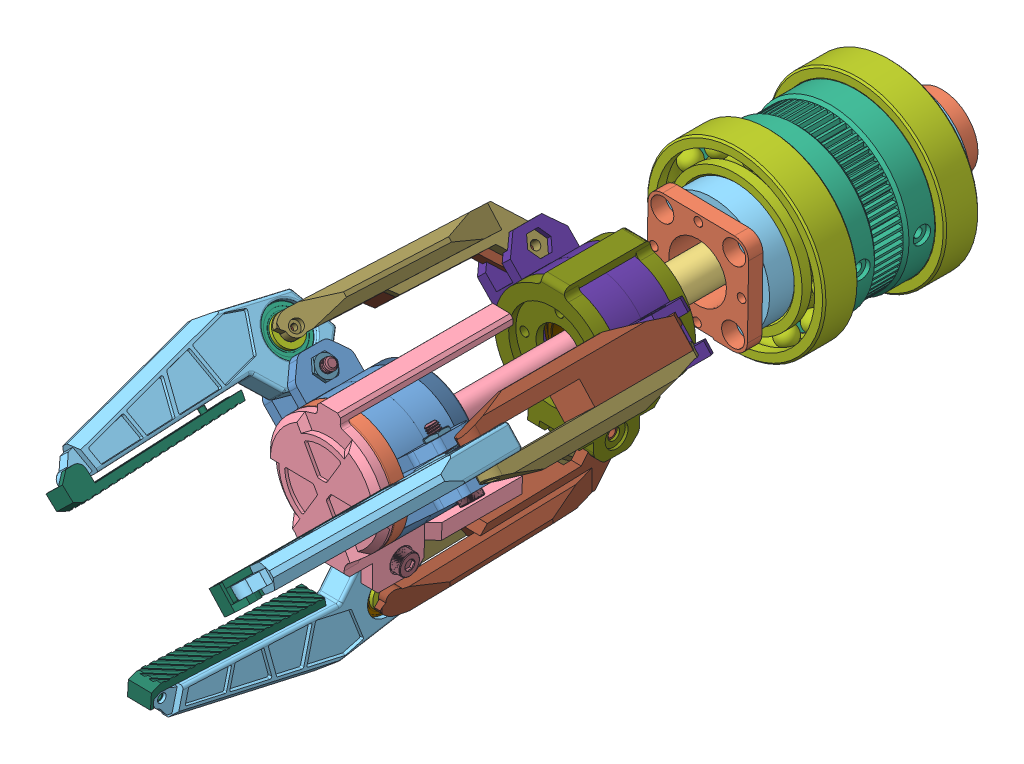
SolidWorks assembly CrawAssemV1.2, configuration EX2. Lengths in mm.
Overall size (95.83 96.83 278.95).
52 component instances, 26 part files, 110 mates.
Components (placement in the parent):
- CrawPivotL-1: CrawPivotL [Default] at (23.6534 28.2906 36.4169) x (0.675201 -0.737634 0) z (0 0 1)
- RotorInner-1: RotorInner [Default] at (23.6534 28.2906 51.4169) x (-0.675201 0.737634 0) z (0 0 -1)
- 4668K131_Permanently Lubricated Stainless Steel Ball Bearing-1: 4668K131_Permanently Lubricated Stainless Steel Ball Bearing [4668K131] at (23.6534 28.2906 52.4169) x (0.977927 0.208948 0) z (0 0 1)
- RotorOutter-1: RotorOutter [Default] at (23.6534 28.2906 56.4169) x (-0.999871 0.016078 0) z (0 0 -1)
- CrawPivotL-2: CrawPivotL [Default] at (23.6534 28.2906 36.4169) x (-0.716673 -0.697409 0) z (0 0 -1)
- FrontCraw-1: FrontCraw [Default] at (-7.9204 40.6623 113.525) x (-0.024761 0.025445 -0.99937) z (0.69697 -0.716221 -0.035504)
- FrontCraw-2: FrontCraw [Default] at (49.7643 43.7862 113.4714) x (0.035168 0.032192 -0.998863) z (-0.736795 -0.674433 -0.047677)
- 4668K334_Permanently Lubricated Stainless Steel Ball Bearing-1: 4668K334_Permanently Lubricated Stainless Steel Ball Bearing [4668K334] at (58.2277 46.2461 36.989) x (0.461728 0.422648 0.779857) z (-0.675201 0.737634 0)
- BearingStop1-1: BearingStop1 [Default] at (56.5397 48.0902 36.989) x (-0.727461 -0.665889 0.165503) z (0.675201 -0.737634 0)
- 4668K334_Permanently Lubricated Stainless Steel Ball Bearing-2: 4668K334_Permanently Lubricated Stainless Steel Ball Bearing [4668K334] at (-9.9873 48.3784 36.952) x (0.471273 -0.484291 0.737132) z (-0.716673 -0.697409 0)
- BearingStop1-2: BearingStop1 [Default] at (-11.779 46.6349 36.952) x (-0.683695 0.702579 -0.197341) z (0.716673 0.697409 0)
- BearingStop2-1: BearingStop2 [Default] at (55.6957 49.0123 36.989) x (-0.727461 -0.665889 0.165503) z (0.675201 -0.737634 0)
- BearingStop2-2: BearingStop2 [Default] at (-12.6749 45.7632 36.952) x (-0.683695 0.702579 -0.197341) z (0.716673 0.697409 0)
- FrontCraw-3: FrontCraw [Default] at (27.1452 -3.3521 113.4714) x (-0.000767 -0.047671 -0.998863) z (0.016059 0.998734 -0.047677)
- 7804K117_Stainless Steel Ball Bearing-1: 7804K117_Stainless Steel Ball Bearing [7804K117] at (23.1186 -11.1922 36.989) x (-0.007051 -0.438494 -0.898707) z (0.999871 -0.016078 0)
- BearingStop2-3: BearingStop2 [Default] at (19.3691 -11.1319 36.989) x (0.016038 0.997394 0.070343) z (0.999871 -0.016078 0)
- BearingStop1-3: BearingStop1 [Default] at (20.6189 -11.152 36.989) x (0.016038 0.997394 0.070343) z (0.999871 -0.016078 0)
- RotorInnerBack-1: RotorInnerBack [Default] at (23.6534 28.2906 21.4169) x (0.962311 -0.271952 0) z (0 0 1)
- SEC2pull1-1: SEC2pull1 [Default] at (-10.6231 40.787 37.118) x (0.023165 -0.023805 -0.999448) z (0.716673 0.697409 0)
- SEC2pull2-1: SEC2pull2 [Default] at (-3.4564 47.7611 37.118) x (0.023165 -0.023805 -0.999448) z (0.716673 0.697409 0)
- 91290A164_Black-Oxide Alloy Steel Socket Head Screw-1: 91290A164_Black-Oxide Alloy Steel Socket Head Screw [91290A164] at (23.2113 0.7942 36.4169) x (0.000258 0.016076 -0.999871) z (0.999871 -0.016078 0)
- 90592A090_Steel Hex Nut (1)-1: 90592A090_Steel Hex Nut (1) [90592A090] at (14.6124 0.9324 36.4169) x (0.016078 0.999871 0) z (0 0 1)
- 91290A164_Black-Oxide Alloy Steel Socket Head Screw-2: 91290A164_Black-Oxide Alloy Steel Socket Head Screw [91290A164] at (-0.6785 40.3897 36.4169) x (-0.0003 0.000308 -1) z (-0.716673 -0.697409 0)
- 90592A090_Steel Hex Nut (1)-2: 90592A090_Steel Hex Nut (1) [90592A090] at (4.0516 44.9926 36.4169) x (-0.348705 0.358336 -0.866025) z (-0.603974 0.620657 0.5)
- 91290A164_Black-Oxide Alloy Steel Socket Head Screw-3: 91290A164_Black-Oxide Alloy Steel Socket Head Screw [91290A164] at (48.6435 38.9643 36.4169) x (-0.209995 -0.192222 0.95862) z (0.675201 -0.737634 0)
- 90592A090_Steel Hex Nut (1)-3: 90592A090_Steel Hex Nut (1) [90592A090] at (44.1872 43.8327 36.4169) x (-0.368817 -0.3376 -0.866025) z (-0.63881 -0.584741 0.5)
- UpperSecCraw (1)-1: UpperSecCraw (1) [Default] at (-7.216 44.2401 113.6369) x (-0.024761 0.025445 -0.99937) z (0.716673 0.697409 0)
- UpperSecCraw (1)-2: UpperSecCraw (1) [Default] at (24.1122 -5.3749 113.6086) x (-0.000767 -0.047671 -0.998863) z (-0.999871 0.016078 0)
- UpperSecCraw (1)-3: UpperSecCraw (1) [Default] at (53.3178 42.9719 113.6086) x (0.035168 0.032192 -0.998863) z (0.675201 -0.737634 0)
- RTL-1: RTL [Default] at (23.6534 28.2906 -18.4955) x (-0.999871 0.016078 0) z (0 0 -1)
- PullPivot-1: PullPivot [Default] at (23.6534 28.2906 -38.4955) x (0.675201 -0.737634 0) z (0 0 1)
- 5972K213_Ball Bearing-1: 5972K213_Ball Bearing [5972K213] at (23.6534 28.2906 -33.4955)
- PullPivot2-1: PullPivot2 [Default] at (23.6534 28.2906 -38.4955) x (0.999025 -0.044147 0) z (0 0 1)
- PullPivot-2: PullPivot [Default] at (23.6534 28.2906 -38.4955) x (-0.716673 -0.697409 0) z (0 0 -1)
- 5972K213_Ball Bearing-2: 5972K213_Ball Bearing [5972K213] at (23.6534 28.2906 -43.4955) x (0.923728 0.383049 0) z (0 0 -1)
- PullPivot2-2: PullPivot2 [Default] at (23.6534 28.2906 -38.4955) x (-0.716673 -0.697409 0) z (0 0 -1)
- SEC2pull1-4: SEC2pull1 [Default] at (50.6589 47.1131 37.1398) x (-0.022244 -0.020361 -0.999545) z (0.675201 -0.737634 0)
- SEC2pull1-5: SEC2pull1 [Default] at (29.1982 -6.2916 37.1398) x (0.000485 0.030152 -0.999545) z (-0.999871 0.016078 0)
- SEC2pull2-7: SEC2pull2 [Default] at (19.5494 -6.1365 37.1398) x (0.000485 0.030152 -0.999545) z (-0.999871 0.016078 0)
- SEC2pull2-8: SEC2pull2 [Default] at (57.4109 39.7367 37.1398) x (-0.022244 -0.020361 -0.999545) z (0.675201 -0.737634 0)
- CylinderTube-1: CylinderTube [Default] at (23.6534 28.2906 -74.2503) x (-0.999871 0.016078 0) z (-0.016078 -0.999871 0)
- Hydro2-2: Hydro2 [Default] at (23.6534 28.2906 -50.4955) x (-0.999871 0.016078 0) z (0 0 -1) size (30 30 73)
- 6112K44_Linear Motion Shaft-1: 6112K44_Linear Motion Shaft [6112K44] at (23.6534 28.2906 -52.5831) x (-0.201275 -0.979535 0) z (0 0 1) size (8 8 100)
- Cylinder40mmCover-1: Cylinder40mmCover [Default] at (23.6534 28.2906 -79.2503) x (-0.999871 0.016078 0) z (0 0 -1) size (40 40 70)
- PiV1-1: PiV1 [Default] at (23.6534 28.2906 -129.2503) x (0.999871 -0.016078 0) z (0 0 1) size (55 55 30)
- PiVEnclosure1-1: PiVEnclosure1 [Default] at (23.6534 28.2906 -109.2503) x (0.791208 -0.611547 0) z (0 0 1) size (75 75 13) (hidden)
- 4668K334_Permanently Lubricated Stainless Steel Ball Bearing-3: 4668K334_Permanently Lubricated Stainless Steel Ball Bearing [4668K334] at (19.2674 62.5359 -106.7503) (hidden)
- 4668K334_Permanently Lubricated Stainless Steel Ball Bearing-4: 4668K334_Permanently Lubricated Stainless Steel Ball Bearing [4668K334] at (-10.5918 23.9046 -106.7503) (hidden)
- 4668K334_Permanently Lubricated Stainless Steel Ball Bearing-5: 4668K334_Permanently Lubricated Stainless Steel Ball Bearing [4668K334] at (28.0395 -5.9546 -106.7503) (hidden)
- 4668K334_Permanently Lubricated Stainless Steel Ball Bearing-6: 4668K334_Permanently Lubricated Stainless Steel Ball Bearing [4668K334] at (57.8987 32.6767 -106.7503) (hidden)
- 5972K249_Ball Bearing-1: 5972K249_Ball Bearing [5972K249] at (23.6534 28.2906 -93.2503) x (0.88466 0.466238 0) z (0 0 1) size (62 62 12)
- 5972K249_Ball Bearing-2: 5972K249_Ball Bearing [5972K249] at (23.6534 28.2906 -135.2503) x (0.910111 -0.414364 0) z (0 0 1) size (62 62 12)
Mates (geometry in assembly coordinates):
- Concentric1: concentric aligned: cylinder of CrawPivotL-1 through (36.9309 40.4442 36.4169) axis (0 0 1) radius 1.3; cylinder of RotorInner-1 through (36.9309 40.4442 43.4169) axis (0 0 1) radius 1.15
- Concentric2: concentric aligned: circle of CrawPivotL-1; cylinder of RotorInner-1 through (40.8175 22.8689 43.4169) axis (0 0 1) radius 1.15
- Coincident2: coincident anti-aligned: plane of CrawPivotL-1 through (23.6534 28.2906 46.4169) normal (0 0 1); plane of RotorInner-1 through (23.6534 28.2906 46.4169) normal (0 0 -1)
- Concentric3: concentric anti-aligned: cylinder of RotorInner-1 through (23.6534 28.2906 54.9169) axis (0 0 -1) radius 3.85; cylinder of 4668K131_Permanently Lubricated Stainless Steel Ball Bearing-1 through (23.6534 28.2906 54.4169) axis (0 0 1) radius 4
- Coincident3: coincident anti-aligned: plane of RotorInner-1 through (23.6534 28.2906 50.4169) normal (0 0 1); plane of 4668K131_Permanently Lubricated Stainless Steel Ball Bearing-1 through (22.4926 33.7235 50.4169) normal (0 0 -1)
- Concentric4: concentric anti-aligned: cylinder of 4668K131_Permanently Lubricated Stainless Steel Ball Bearing-1 through (23.6534 28.2906 54.4169) axis (0 0 1) radius 8; cylinder of RotorOutter-1 through (23.6534 28.2906 54.4169) axis (0 0 -1) radius 8
- Coincident4: coincident anti-aligned: plane of 4668K131_Permanently Lubricated Stainless Steel Ball Bearing-1 through (22.0237 35.9184 54.4169) normal (0 0 1); plane of RotorOutter-1 through (23.6534 28.2906 54.4169) normal (0 0 -1)
- Coincident5: coincident anti-aligned: plane of CrawPivotL-1 through (23.6534 28.2906 36.4169) normal (0 0 -1); plane of CrawPivotL-2 through (23.6534 28.2906 36.4169) normal (0 0 1)
- Coincident6: coincident anti-aligned: circle of CrawPivotL-1; circle of CrawPivotL-2
- Concentric7: concentric anti-aligned: cylinder of FrontCraw-2 through (56.5397 48.0902 36.989) axis (0.675201 -0.737634 0) radius 8; cylinder of 4668K334_Permanently Lubricated Stainless Steel Ball Bearing-1 through (56.5397 48.0902 36.989) axis (-0.675201 0.737634 0) radius 8
- Coincident10: coincident anti-aligned: plane of FrontCraw-2 through (56.5397 48.0902 36.989) normal (0.675201 -0.737634 0); plane of 4668K334_Permanently Lubricated Stainless Steel Ball Bearing-1 through (60.9979 52.1711 32.1378) normal (-0.675201 0.737634 0)
- Concentric8: concentric aligned: cylinder of 4668K334_Permanently Lubricated Stainless Steel Ball Bearing-1 through (56.5397 48.0902 36.989) axis (-0.675201 0.737634 0) radius 4; cylinder of BearingStop1-1 through (59.9157 44.4021 36.989) axis (-0.675201 0.737634 0) radius 3.9
- Coincident11: coincident anti-aligned: plane of 4668K334_Permanently Lubricated Stainless Steel Ball Bearing-1 through (63.0477 47.2689 33.581) normal (0.675201 -0.737634 0); plane of BearingStop1-1 through (59.9157 44.4021 36.989) normal (-0.675201 0.737634 0)
- Concentric9: concentric anti-aligned: cylinder of FrontCraw-1 through (-11.779 46.6349 36.952) axis (0.716673 0.697409 0) radius 8; cylinder of 4668K334_Permanently Lubricated Stainless Steel Ball Bearing-2 through (-11.779 46.6349 36.952) axis (-0.716673 -0.697409 0) radius 8
- Coincident12: coincident anti-aligned: plane of FrontCraw-1 through (-11.779 46.6349 36.952) normal (0.716673 0.697409 0); plane of 4668K334_Permanently Lubricated Stainless Steel Ball Bearing-2 through (-15.7632 50.7291 42.189) normal (-0.716673 -0.697409 0)
- Concentric11: concentric aligned: cylinder of 4668K334_Permanently Lubricated Stainless Steel Ball Bearing-2 through (-11.779 46.6349 36.952) axis (-0.716673 -0.697409 0) radius 4; cylinder of BearingStop1-2 through (-8.1957 50.122 36.952) axis (-0.716673 -0.697409 0) radius 3.9
- Coincident13: coincident anti-aligned: plane of 4668K334_Permanently Lubricated Stainless Steel Ball Bearing-2 through (-10.9946 52.9982 40.631) normal (0.716673 0.697409 0); plane of BearingStop1-2 through (-8.1957 50.122 36.952) normal (-0.716673 -0.697409 0)
- Concentric12: concentric aligned: cylinder of BearingStop1-1 through (60.7598 43.48 36.989) axis (-0.675201 0.737634 0) radius 3.05; cylinder of BearingStop2-1 through (60.591 43.6644 36.989) axis (-0.675201 0.737634 0) radius 2.95
- Coincident15: coincident anti-aligned: circle of BearingStop1-1; plane of BearingStop2-1 through (56.5397 48.0902 36.989) normal (0.675201 -0.737634 0)
- Concentric13: concentric aligned: cylinder of BearingStop1-2 through (-7.2998 50.9937 36.952) axis (-0.716673 -0.697409 0) radius 3.05; cylinder of BearingStop2-2 through (-7.479 50.8194 36.952) axis (-0.716673 -0.697409 0) radius 2.95
- Coincident17: coincident anti-aligned: plane of BearingStop1-2 through (-11.779 46.6349 36.952) normal (-0.716673 -0.697409 0); plane of BearingStop2-2 through (-11.779 46.6349 36.952) normal (0.716673 0.697409 0)
- Concentric14: concentric aligned: circle of RotorOutter-1; circle of FrontCraw-3
- Coincident18: coincident anti-aligned: plane of RotorOutter-1 through (27.1465 -3.2696 56.4169) normal (-0.999871 0.016078 0); plane of FrontCraw-3 through (27.1452 -3.3521 113.4714) normal (0.999871 -0.016078 0)
- Concentric15: concentric anti-aligned: cylinder of FrontCraw-3 through (25.6183 -11.2324 36.989) axis (-0.999871 0.016078 0) radius 8; cylinder of 7804K117_Stainless Steel Ball Bearing-1 through (25.6183 -11.2324 36.989) axis (0.999871 -0.016078 0) radius 8
- Coincident20: coincident anti-aligned: plane of FrontCraw-3 through (25.6183 -11.2324 36.989) normal (-0.999871 0.016078 0); plane of 7804K117_Stainless Steel Ball Bearing-1 through (25.698 -6.2754 34.5697) normal (0.999871 -0.016078 0)
- Concentric16: concentric anti-aligned: cylinder of 7804K117_Stainless Steel Ball Bearing-1 through (25.6183 -11.2324 36.989) axis (0.999871 -0.016078 0) radius 4; cylinder of BearingStop1-3 through (25.6183 -11.2324 36.989) axis (-0.999871 0.016078 0) radius 3.9
- Coincident21: coincident anti-aligned: plane of 7804K117_Stainless Steel Ball Bearing-1 through (25.698 -6.2754 34.5697) normal (0.999871 -0.016078 0); plane of BearingStop1-3 through (25.6183 -11.2324 36.989) normal (-0.999871 0.016078 0)
- Concentric17: concentric aligned: cylinder of BearingStop2-3 through (26.6181 -11.2485 36.989) axis (-0.999871 0.016078 0) radius 2.95; cylinder of BearingStop1-3 through (26.8681 -11.2525 36.989) axis (-0.999871 0.016078 0) radius 3.05
- Coincident23: coincident anti-aligned: plane of 7804K117_Stainless Steel Ball Bearing-1 through (20.6803 -7.333 35.1252) normal (-0.999871 0.016078 0); plane of BearingStop2-3 through (20.6189 -11.152 36.989) normal (0.999871 -0.016078 0)
- Concentric18: concentric aligned: cylinder of CrawPivotL-2 through (28.5486 45.6122 36.4169) axis (0 0 -1) radius 1.3; cylinder of RotorInnerBack-1 through (28.5486 45.6122 29.4169) axis (0 0 -1) radius 0.725
- Concentric19: concentric aligned: cylinder of CrawPivotL-2 through (11.1001 41.1907 36.4169) axis (0 0 -1) radius 1.3; cylinder of RotorInnerBack-1 through (11.1001 41.1907 29.4169) axis (0 0 -1) radius 0.725
- Coincident24: coincident anti-aligned: plane of CrawPivotL-2 through (23.6534 28.2906 26.4169) normal (0 0 -1); plane of RotorInnerBack-1 through (23.6534 28.2906 26.4169) normal (0 0 1)
- Concentric26: concentric aligned: cylinder of BearingStop2-2 through (-7.479 50.8194 36.952) axis (-0.716673 -0.697409 0) radius 2.05; cylinder of SEC2pull1-1 through (-6.9415 51.3424 36.952) axis (-0.716673 -0.697409 0) radius 1.8
- Coincident28: coincident anti-aligned: plane of BearingStop2-2 through (-12.6749 45.7632 36.952) normal (-0.716673 -0.697409 0); plane of SEC2pull1-1 through (-12.6749 45.7632 36.952) normal (0.716673 0.697409 0)
- Coincident32: coincident anti-aligned: circle of SEC2pull1-1; circle of SEC2pull2-1
- Concentric29: concentric aligned: circle of SEC2pull1-1; cylinder of SEC2pull2-1 through (-8.0165 50.2963 36.952) axis (0.716673 0.697409 0) radius 1
- Concentric35: concentric anti-aligned: circle of RotorOutter-1; circle of 91290A164_Black-Oxide Alloy Steel Socket Head Screw-1
- Coincident38: coincident anti-aligned: plane of RotorOutter-1 through (30.2104 0.6816 36.4169) normal (0.999871 -0.016078 0); plane of 91290A164_Black-Oxide Alloy Steel Socket Head Screw-1 through (30.2096 0.6286 39.7164) normal (-0.999871 0.016078 0)
- Concentric36: concentric anti-aligned: circle of RotorOutter-1; circle of 90592A090_Steel Hex Nut (1)-1
- Coincident39: coincident anti-aligned: plane of RotorOutter-1 through (16.6544 28.4032 56.4169) normal (-0.999871 0.016078 0); plane of 90592A090_Steel Hex Nut (1)-1 through (16.1559 -2.5928 34.3961) normal (0.999871 -0.016078 0)
- Coincident40: coincident aligned: circle of CrawPivotL-2; circle of 91290A164_Black-Oxide Alloy Steel Socket Head Screw-2
- Coincident41: coincident aligned: circle of CrawPivotL-2; circle of 90592A090_Steel Hex Nut (1)-2
- Coincident42: coincident anti-aligned: plane of CrawPivotL-2 through (0.464 46.3851 34.3961) normal (0.697409 -0.716673 0); plane of 90592A090_Steel Hex Nut (1)-2 through (0.464 46.3851 38.4376) normal (-0.697409 0.716673 0)
- Coincident43: coincident anti-aligned: plane of RotorOutter-1 through (16.2685 4.4063 38.4376) normal (-0.016078 -0.999871 0); plane of 90592A090_Steel Hex Nut (1)-1 through (13.0689 4.4577 38.4376) normal (0.016078 0.999871 0)
- Coincident44: coincident anti-aligned: plane of CrawPivotL-2 through (-14.723 47.6528 46.4169) normal (0.716673 0.697409 0); plane of FrontCraw-1 through (-7.9204 40.6623 113.525) normal (-0.716673 -0.697409 0)
- Coincident45: coincident aligned: circle of CrawPivotL-1; circle of 91290A164_Black-Oxide Alloy Steel Socket Head Screw-3
- Coincident46: coincident aligned: circle of CrawPivotL-1; circle of 90592A090_Steel Hex Nut (1)-3
- Coincident47: coincident anti-aligned: plane of CrawPivotL-1 through (47.8492 45.0157 38.4376) normal (-0.737634 -0.675201 0); plane of 90592A090_Steel Hex Nut (1)-3 through (47.8492 45.0157 34.3961) normal (0.737634 0.675201 0)
- Concentric39: concentric anti-aligned: cylinder of FrontCraw-1 through (-9.366 42.1478 113.6369) axis (0.716673 0.697409 0) radius 2; cylinder of UpperSecCraw (1)-1 through (-5.066 46.3323 113.6369) axis (-0.716673 -0.697409 0) radius 1.975
- Coincident49: coincident anti-aligned: plane of FrontCraw-1 through (-9.8607 51.2595 115.1168) normal (0.716673 0.697409 0); plane of UpperSecCraw (1)-1 through (-5.066 46.3323 113.6369) normal (-0.716673 -0.697409 0)
- Parallel1: parallel anti-aligned: plane of FrontCraw-1 through (-2.1871 46.2416 113.525) normal (0.69697 -0.716221 -0.035504); plane of UpperSecCraw (1)-1 through (-5.987 44.411 68.9439) normal (-0.69697 0.716221 0.035504)
- Concentric40: concentric anti-aligned: cylinder of FrontCraw-3 through (27.1119 -5.4231 113.6086) axis (-0.999871 0.016078 0) radius 2; cylinder of UpperSecCraw (1)-2 through (21.1126 -5.3267 113.6086) axis (0.999871 -0.016078 0) radius 1.975
- Coincident52: coincident anti-aligned: plane of FrontCraw-3 through (21.0024 -12.1823 115.1721) normal (-0.999871 0.016078 0); plane of UpperSecCraw (1)-2 through (21.1126 -5.3267 113.6086) normal (0.999871 -0.016078 0)
- Parallel3: parallel anti-aligned: plane of FrontCraw-3 through (19.1462 -3.2235 113.4714) normal (0.016059 0.998734 -0.047677); plane of UpperSecCraw (1)-2 through (23.1154 -5.1688 68.91) normal (-0.016059 -0.998734 0.047677)
- Concentric41: concentric anti-aligned: cylinder of FrontCraw-2 through (51.2922 45.1848 113.6086) axis (0.675201 -0.737634 0) radius 2; cylinder of UpperSecCraw (1)-3 through (55.3434 40.759 113.6086) axis (-0.675201 0.737634 0) radius 1.975
- Coincident54: coincident anti-aligned: plane of FrontCraw-2 through (60.401 45.3885 115.1721) normal (0.675201 -0.737634 0); plane of UpperSecCraw (1)-3 through (55.3434 40.759 113.6086) normal (-0.675201 0.737634 0)
- Parallel4: parallel anti-aligned: plane of FrontCraw-2 through (55.1659 37.8852 113.4714) normal (-0.736795 -0.674433 -0.047677); plane of UpperSecCraw (1)-3 through (53.8528 42.1059 68.91) normal (0.736795 0.674433 0.047677)
- Coincident59: coincident anti-aligned: circle of RTL-1; circle of PullPivot-1
- Concentric49: concentric aligned: cylinder of PullPivot-1 through (23.6534 28.2906 -38.4955) axis (0 0 1) radius 12; cylinder of 5972K213_Ball Bearing-1 through (23.6534 28.2906 -30.9955) axis (0 0 1) radius 12
- Coincident61: coincident anti-aligned: plane of PullPivot-1 through (23.6534 28.2906 -30.9955) normal (0 0 -1); plane of 5972K213_Ball Bearing-1 through (23.6534 40.0406 -30.9955) normal (0 0 1)
- Coincident62: coincident anti-aligned: circle of PullPivot-1; circle of PullPivot2-1
- Concentric50: concentric aligned: cylinder of PullPivot-1 through (12.5889 18.1626 -28.4955) axis (0 0 -1) radius 2; cylinder of PullPivot2-1 through (12.5889 18.1626 -35.9955) axis (0 0 -1) radius 2
- Concentric52: concentric anti-aligned: circle of RotorInnerBack-1; circle of RTL-1
- Concentric53: concentric aligned: cylinder of PullPivot-2 through (23.6534 28.2906 -38.4955) axis (0 0 -1) radius 12; cylinder of 5972K213_Ball Bearing-2 through (23.6534 28.2906 -45.9955) axis (0 0 -1) radius 12
- Coincident65: coincident anti-aligned: plane of PullPivot-2 through (23.6534 28.2906 -45.9955) normal (0 0 1); plane of 5972K213_Ball Bearing-2 through (28.1543 17.4368 -45.9955) normal (0 0 -1)
- Coincident66: coincident anti-aligned: circle of PullPivot-2; circle of PullPivot2-2
- Concentric54: concentric aligned: cylinder of PullPivot-2 through (23.8578 43.2892 -48.4955) axis (0 0 1) radius 2; cylinder of PullPivot2-2 through (23.8578 43.2892 -40.9955) axis (0 0 1) radius 2
- Coincident67: coincident aligned: circle of RTL-1; circle of PullPivot-2
- Concentric56: concentric aligned: cylinder of BearingStop2-1 through (60.591 43.6644 36.989) axis (-0.675201 0.737634 0) radius 2.05; cylinder of SEC2pull1-4 through (61.0974 43.1112 36.989) axis (-0.675201 0.737634 0) radius 1.8
- Coincident68: coincident anti-aligned: plane of BearingStop2-1 through (55.6957 49.0123 36.989) normal (-0.675201 0.737634 0); plane of SEC2pull1-4 through (55.6957 49.0123 36.989) normal (0.675201 -0.737634 0)
- Coincident72: coincident anti-aligned: plane of SEC2pull1-4 through (61.0974 43.1112 36.989) normal (0.675201 -0.737634 0); plane of SEC2pull2-8 through (61.0974 43.1112 36.989) normal (-0.675201 0.737634 0)
- Concentric63: concentric anti-aligned: cylinder of SEC2pull1-4 through (44.491 43.5008 -38.4955) axis (0.675201 -0.737634 0) radius 1.5; cylinder of SEC2pull2-8 through (53.6062 33.5427 -38.4955) axis (-0.675201 0.737634 0) radius 1.5
- Concentric65: concentric anti-aligned: cylinder of BearingStop2-3 through (26.6181 -11.2485 36.989) axis (-0.999871 0.016078 0) radius 2.05; cylinder of SEC2pull1-5 through (19.1191 -11.1279 36.989) axis (0.999871 -0.016078 0) radius 1.8
- Coincident73: coincident anti-aligned: plane of BearingStop2-3 through (26.6181 -11.2485 36.989) normal (0.999871 -0.016078 0); plane of SEC2pull1-5 through (26.6181 -11.2485 36.989) normal (-0.999871 0.016078 0)
- Concentric66: concentric anti-aligned: cylinder of SEC2pull1-5 through (29.1178 -11.2887 36.989) axis (-0.999871 0.016078 0) radius 0.5; circle of SEC2pull2-7
- Coincident74: coincident anti-aligned: plane of BearingStop2-3 through (19.969 -11.1416 36.989) normal (-0.999871 0.016078 0); plane of SEC2pull2-7 through (19.969 -11.1416 36.989) normal (0.999871 -0.016078 0)
- Concentric67: concentric anti-aligned: cylinder of SEC2pull1-5 through (30.8103 0.672 -38.4955) axis (-0.999871 0.016078 0) radius 1.5; cylinder of SEC2pull2-7 through (17.662 0.8834 -38.4955) axis (0.999871 -0.016078 0) radius 1.5
- Concentric73: concentric anti-aligned: cylinder of PullPivot-1 through (29.0627 60.3557 -38.4955) axis (0.675201 -0.737634 0) radius 2; cylinder of SEC2pull2-8 through (53.6062 33.5427 -38.4955) axis (-0.675201 0.737634 0) radius 1.5
- Concentric77: concentric aligned: cylinder of RTL-1 through (43.2087 0.4726 -38.4955) axis (-0.999871 0.016078 0) radius 2.05; cylinder of SEC2pull1-5 through (30.8103 0.672 -38.4955) axis (-0.999871 0.016078 0) radius 1.5
- Tangent1: tangent aligned: cylinder of FrontCraw-1 through (-4.4187 37.0639 36.5259) axis (0.716673 0.697409 0) radius 2.25; cylinder of 91290A164_Black-Oxide Alloy Steel Socket Head Screw-2 through (7.2049 48.0612 36.4169) axis (0.716673 0.697409 0) radius 2
- Concentric80: concentric anti-aligned: cylinder of FrontCraw-2 through (46.7529 41.0297 36.4169) axis (0.675201 -0.737634 0) radius 2.25; cylinder of 91290A164_Black-Oxide Alloy Steel Socket Head Screw-3 through (41.2163 47.0783 36.4169) axis (-0.675201 0.737634 0) radius 2
- Parallel9: parallel aligned: plane of RotorOutter-1 through (20.0333 51.9478 -5.5831) normal (0.016078 0.999871 0); plane of CylinderTube-1 through (41.4325 45.507 -79.2503) normal (0.016078 0.999871 0)
- Concentric89: concentric aligned: cylinder of SEC2pull1-4 through (54.3453 50.4875 36.989) axis (0.675201 -0.737634 0) radius 0.5; cylinder of SEC2pull2-8 through (60.0846 44.2176 36.989) axis (0.675201 -0.737634 0) radius 1
- Concentric90: concentric anti-aligned: cylinder of RTL-1 through (23.6534 28.2906 -18.4955) axis (0 0 -1) radius 15; cylinder of Hydro2-2 through (23.6534 28.2906 -53.4955) axis (0 0 1) radius 15
- Concentric91: concentric aligned: cylinder of RTL-1 through (23.8383 39.7891 -48.4955) axis (0 0 -1) radius 2; cylinder of Hydro2-2 through (23.8383 39.7891 -50.4955) axis (0 0 -1) radius 2
- Coincident85: coincident anti-aligned: plane of RTL-1 through (23.6534 28.2906 -50.4955) normal (0 0 -1); plane of Hydro2-2 through (23.6534 28.2906 -50.4955) normal (0 0 1)
- Concentric92: concentric anti-aligned: cylinder of Hydro2-2 through (23.6534 28.2906 -110.4955) axis (0 0 1) radius 4.1; cylinder of 6112K44_Linear Motion Shaft-1 through (23.6534 28.2906 47.4169) axis (0 0 -1) radius 4
- Coincident86: coincident anti-aligned: plane of RotorInner-1 through (23.6534 28.2906 47.4169) normal (0 0 -1); plane of 6112K44_Linear Motion Shaft-1 through (23.6534 28.2906 47.4169) normal (0 0 1)
- Concentric94: concentric aligned: cylinder of CylinderTube-1 through (23.6534 28.2906 -159.2503) axis (0 0 1) radius 12.5; cylinder of Hydro2-2 through (23.6534 28.2906 -123.4955) axis (0 0 1) radius 8.5
- Concentric95: concentric aligned: cylinder of CylinderTube-1 through (23.6534 28.2906 -159.2503) axis (0 0 1) radius 12.5; cylinder of Cylinder40mmCover-1 through (23.6534 28.2906 -149.2503) axis (0 0 1) radius 12.6
- Concentric96: concentric aligned: cylinder of CylinderTube-1 through (23.8986 43.5386 -159.2503) axis (0 0 1) radius 1.5; cylinder of Cylinder40mmCover-1 through (23.8986 43.5386 -89.2503) axis (0 0 1) radius 1.5
- Coincident87: coincident anti-aligned: plane of CylinderTube-1 through (23.6534 28.2906 -79.2503) normal (0 0 -1); plane of Cylinder40mmCover-1 through (23.6534 28.2906 -79.2503) normal (0 0 1)
- Concentric97: concentric aligned: cylinder of Cylinder40mmCover-1 through (23.6534 28.2906 -149.2503) axis (0 0 1) radius 20; cylinder of PiV1-1 through (23.6534 28.2906 -129.2503) axis (0 0 1) radius 20.5
- Concentric98: concentric anti-aligned: cylinder of Cylinder40mmCover-1 through (43.6509 27.9691 -124.7503) axis (-0.999871 0.016078 0) radius 1.55; cylinder of PiV1-1 through (-3.843 28.7328 -124.7503) axis (0.999871 -0.016078 0) radius 1.55
- Concentric99: concentric aligned: cylinder of Cylinder40mmCover-1 through (23.6534 28.2906 -149.2503) axis (0 0 1) radius 20; cylinder of PiVEnclosure1-1 through (23.6534 28.2906 -99.2503) axis (0 0 1) radius 22.5
- Coincident89: coincident anti-aligned: plane of PiV1-1 through (23.6534 28.2906 -99.2503) normal (0 0 1); plane of PiVEnclosure1-1 through (23.6534 28.2906 -99.2503) normal (0 0 -1)
- Concentric100: concentric aligned: cylinder of PiVEnclosure1-1 through (57.8987 32.6767 -109.2503) axis (0 0 1) radius 3.9; cylinder of 4668K334_Permanently Lubricated Stainless Steel Ball Bearing-6 through (57.8987 32.6767 -104.2503) axis (0 0 1) radius 4
- Concentric101: concentric aligned: cylinder of PiVEnclosure1-1 through (19.2674 62.5359 -109.2503) axis (0 0 1) radius 3.9; cylinder of 4668K334_Permanently Lubricated Stainless Steel Ball Bearing-3 through (19.2674 62.5359 -104.2503) axis (0 0 1) radius 4
- Concentric102: concentric aligned: cylinder of PiVEnclosure1-1 through (28.0395 -5.9546 -109.2503) axis (0 0 1) radius 3.9; cylinder of 4668K334_Permanently Lubricated Stainless Steel Ball Bearing-5 through (28.0395 -5.9546 -104.2503) axis (0 0 1) radius 4
- Concentric103: concentric aligned: cylinder of PiVEnclosure1-1 through (-10.5918 23.9046 -109.2503) axis (0 0 1) radius 3.9; cylinder of 4668K334_Permanently Lubricated Stainless Steel Ball Bearing-4 through (-10.5918 23.9046 -104.2503) axis (0 0 1) radius 4
- Coincident90: coincident anti-aligned: plane of PiVEnclosure1-1 through (6.5308 26.0976 -104.2503) normal (0 0 -1); plane of 4668K334_Permanently Lubricated Stainless Steel Ball Bearing-4 through (-10.5918 29.349 -104.2503) normal (0 0 1)
- Coincident91: coincident anti-aligned: plane of PiVEnclosure1-1 through (21.4604 45.4133 -104.2503) normal (0 0 -1); plane of 4668K334_Permanently Lubricated Stainless Steel Ball Bearing-3 through (19.2674 67.9803 -104.2503) normal (0 0 1)
- Coincident92: coincident anti-aligned: plane of PiVEnclosure1-1 through (25.8465 11.168 -104.2503) normal (0 0 -1); plane of 4668K334_Permanently Lubricated Stainless Steel Ball Bearing-5 through (28.0395 -0.5102 -104.2503) normal (0 0 1)
- Coincident93: coincident anti-aligned: circle of PiVEnclosure1-1; plane of 4668K334_Permanently Lubricated Stainless Steel Ball Bearing-6 through (57.8987 38.1211 -104.2503) normal (0 0 1)
- Concentric105: concentric aligned: cylinder of Cylinder40mmCover-1 through (23.6534 28.2906 -149.2503) axis (0 0 1) radius 20; cylinder of 5972K249_Ball Bearing-1 through (23.6534 28.2906 -87.2503) axis (0 0 1) radius 19.9995
- Coincident94: coincident anti-aligned: plane of PiV1-1 through (23.6534 28.2906 -99.2503) normal (0 0 1); plane of 5972K249_Ball Bearing-1 through (14.0492 46.5142 -99.2503) normal (0 0 -1)
- Concentric106: concentric aligned: cylinder of Cylinder40mmCover-1 through (23.6534 28.2906 -149.2503) axis (0 0 1) radius 20; cylinder of 5972K249_Ball Bearing-2 through (23.6534 28.2906 -129.2503) axis (0 0 1) radius 19.9995
- Coincident95: coincident anti-aligned: plane of PiV1-1 through (23.6534 28.2906 -129.2503) normal (0 0 -1); plane of 5972K249_Ball Bearing-2 through (33.3089 49.498 -129.2503) normal (0 0 1)
- Coincident96: coincident anti-aligned: plane of CrawPivotL-1 through (33.2413 17.8162 36.4169) normal (-0.675201 0.737634 0); plane of FrontCraw-2 through (55.1659 37.8852 113.4714) normal (0.675201 -0.737634 0)
- Concentric107: concentric anti-aligned: cylinder of SEC2pull1-1 through (-6.6627 34.5663 -38.4955) axis (0.716673 0.697409 0) radius 1.5; cylinder of SEC2pull2-1 through (3.0124 43.9814 -38.4955) axis (-0.716673 -0.697409 0) radius 1.5
